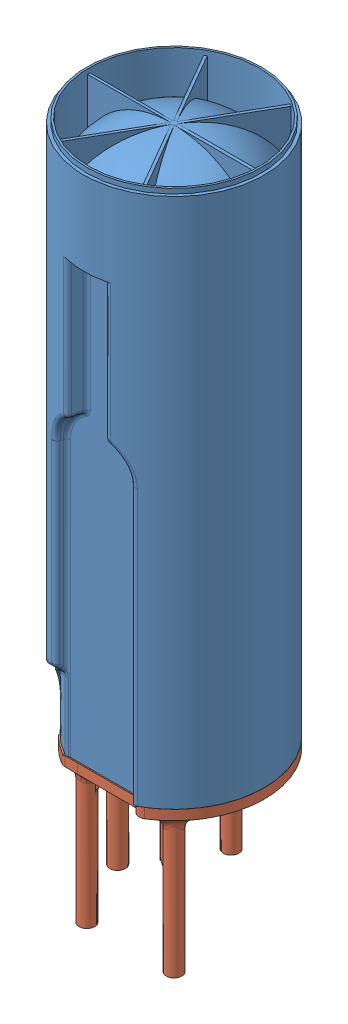
SolidWorks assembly Assem1, configuration Default. Lengths in mm.
Overall size (158 441.33 167.13).
2 component instances, 2 part files, 3 mates.
Components (placement in the parent):
- Cylinder_Chute_Main^ERS_v0.3-1: Cylinder_Chute_Main^ERS_v0.3 [Default] at (110.5592 31.6513 255.7587) size (136.63 349.63 145.75)
- PIZZA_v3.1-1: PIZZA_v3.1 [Default] at (110.5592 25.3013 255.7587) x (-0.5 0 -0.866025) z (0.866025 0 -0.5) size (116.82 99.06 114.78)
Mates (geometry in assembly coordinates):
- Coincident1: coincident: plane of Cylinder_Chute_Main^ERS_v0.3-1 through (110.5592 31.6513 255.7587) normal (0 -1 0); plane of PIZZA_v3.1-1 through (110.5592 31.6513 255.7587) normal (0 1 0)
- Concentric1: concentric: cylinder of Cylinder_Chute_Main^ERS_v0.3-1 through (110.5592 323.7513 255.7587) axis (0 -1 0) radius 58.42; cylinder of PIZZA_v3.1-1 through (110.5592 31.6513 255.7587) axis (0 -1 0) radius 58.42
- Parallel1: parallel aligned: plane of Cylinder_Chute_Main^ERS_v0.3-1 through (110.5592 31.6513 301.4787) normal (0 0 1); plane of PIZZA_v3.1-1 through (110.5592 31.6513 302.2407) normal (0 0 1)
